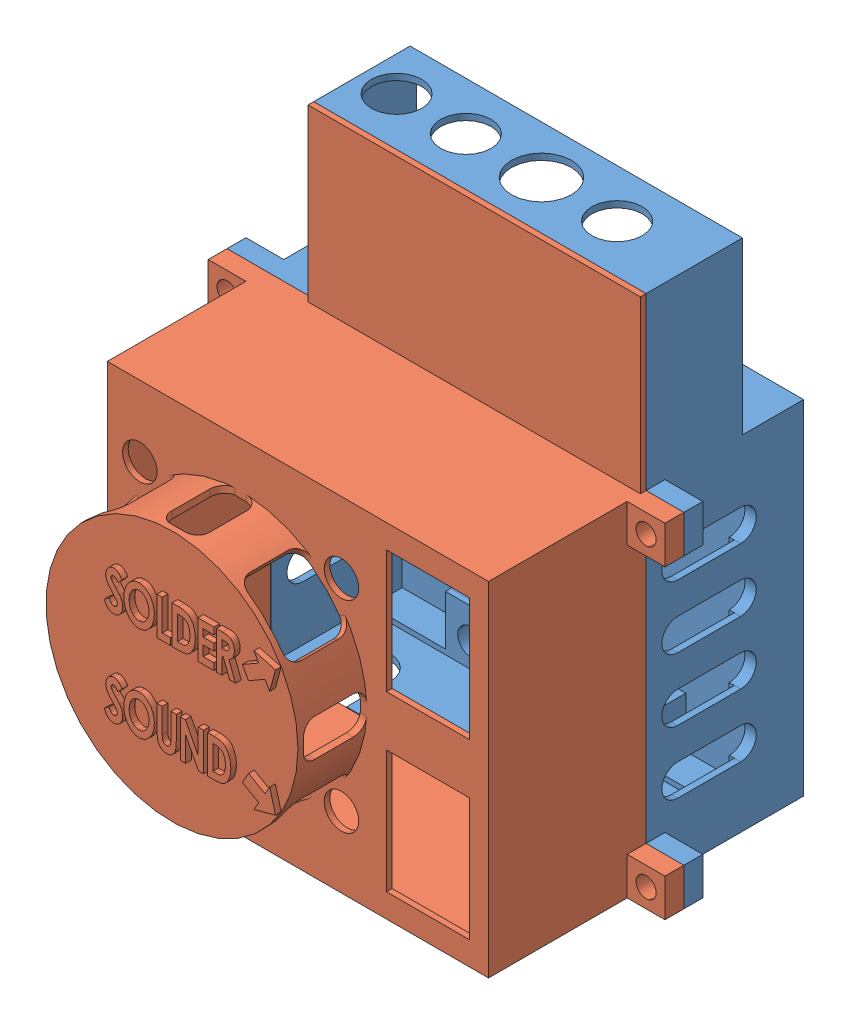
SolidWorks assembly Caja_Full, configuration Predeterminado. Lengths in mm.
Overall size (72.5 82.07 61.8).
2 component instances, 2 part files, 3 mates.
Components (placement in the parent):
- Caja(V2)-1: Caja(V2) [Predeterminado] at (40.727 -2.9872 72.5) size (72.5 81.57 25)
- Caja_Top(V2)-1: Caja_Top(V2) [Predeterminado] at (27.6715 27.3574 122.5) x (1 0 0) z (0 0 -1) size (72.5 82.07 36.8)
Mates (geometry in assembly coordinates):
- Coincidente1: coincident: plane of assembly; plane of assembly; plane of Caja(V2)-1 through (40.727 -2.9872 97.5) normal (0 0 1); plane of Caja_Top(V2)-1 through (27.6715 27.3574 97.5) normal (0 0 -1)
- Concéntrica1: concentric: cylinder of assembly; cylinder of assembly; cylinder of Caja(V2)-1 through (-35.8285 -24.1426 94.5) axis (0 0 1) radius 1.6; cylinder of Caja_Top(V2)-1 through (-35.8285 -24.1426 100.5) axis (0 0 -1) radius 1.6
- Concéntrica2: concentric: cylinder of assembly; cylinder of assembly; cylinder of Caja(V2)-1 through (30.6715 24.3574 94.5) axis (0 0 1) radius 1.6; cylinder of Caja_Top(V2)-1 through (30.6715 24.3574 100.5) axis (0 0 -1) radius 1.6
